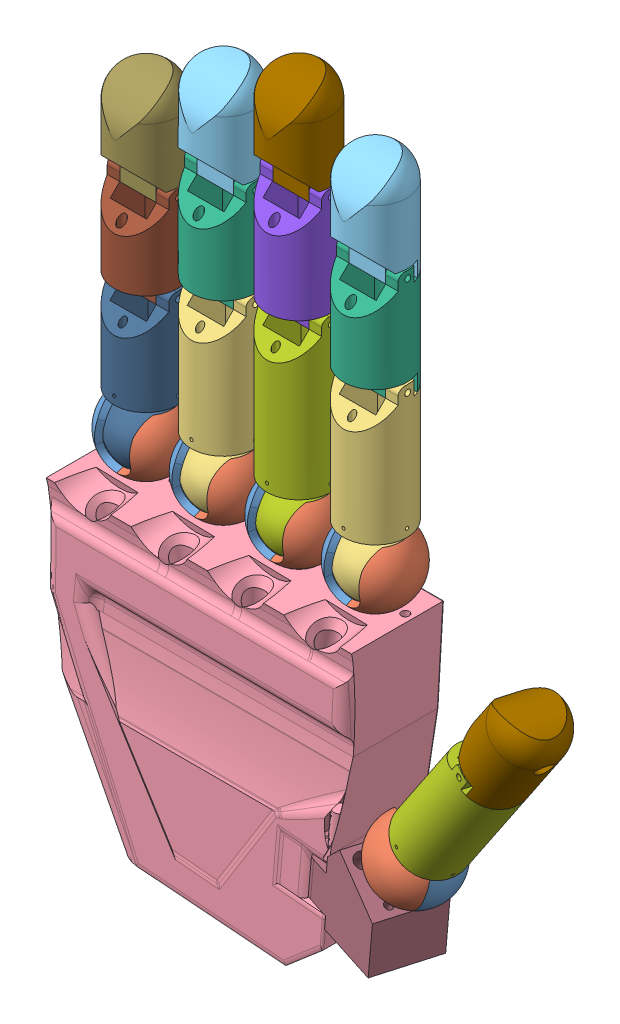
SolidWorks assembly Resized_Assembly, configuration Default. Lengths in mm.
Overall size (156.9 181.99 84.04).
27 component instances, 13 part files, 59 mates.
Components (placement in the parent):
- Resized_Balljoint_socket_L-1: Resized_Balljoint_socket_L [Default] at origin size (9.96 22.72 18.45)
- Resized_Balljoint_socket_R-2: Resized_Balljoint_socket_R [Default] at (-2.2321 0.0027 0.0009) size (9.98 22.72 18.51)
- Resized_BaseDigit_Point&Ring-2: Resized_BaseDigit_Point&Ring [Default] at (-1.1155 37.7951 -0.2751) x (0 -1 0) z (1 0 0) size (50.02 16 16)
- Resized_PalmBody-1: Resized_PalmBody [Default] at (-17.9073 -92.6065 3.3865) x (0.996151 -0.087649 0) z (0 0 1) size (77.61 77.02 24.74)
- Resized_TipDigit_Point&Ring-1: Resized_TipDigit_Point&Ring [Default] at (-1.116 83.4643 -0.063) x (0 -1 0) z (0 0 1) size (25.82 16 16)
- Resized_MiddleDigit2_Point&Ring-2: Resized_MiddleDigit2_Point&Ring [Default] at (-1.116 39.7825 -0.175) x (0 1 0) z (-1 0 0) size (28.43 16 16)
- Resized_BaseDigit_Mid-1: Resized_BaseDigit_Mid [Default] at (-20.5187 37.7951 -0.4783) x (0 -1 0) z (1 0 0) size (55.19 16 16)
- Resized_Balljoint_socket_L-2: Resized_Balljoint_socket_L [Default] at (-19.4032 0 -0.2032) size (9.96 22.72 18.45)
- Resized_Balljoint_socket_R-3: Resized_Balljoint_socket_R [Default] at (-21.6353 0.0027 -0.2023) size (9.98 22.72 18.51)
- Resized_MiddleDigit2_Mid-1: Resized_MiddleDigit2_Mid [Default] at (-20.5192 47.7951 -0.3782) x (0 1 0) z (-1 0 0) size (31.27 16 16)
- Resized_TipDigit_Mid-1: Resized_TipDigit_Mid [Default] at (-20.5192 91.4769 -0.2662) x (0 -1 0) z (0 0 1) size (25.82 16 16)
- Resized_BaseDigit_Point&Ring-3: Resized_BaseDigit_Point&Ring [Default] at (-39.5155 37.7951 -0.4783) x (0 -1 0) z (1 0 0) size (50.02 16 16)
- Resized_MiddleDigit2_Point&Ring-3: Resized_MiddleDigit2_Point&Ring [Default] at (-39.516 39.7825 -0.3782) x (0 1 0) z (-1 0 0) size (28.43 16 16)
- Resized_TipDigit_Point&Ring-2: Resized_TipDigit_Point&Ring [Default] at (-39.516 83.4643 -0.2662) x (0 -1 0) z (0 0 1) size (25.82 16 16)
- Resized_Balljoint_socket_L-3: Resized_Balljoint_socket_L [Default] at (-57.6 0 0) size (9.96 22.72 18.45)
- Resized_Balljoint_socket_R-4: Resized_Balljoint_socket_R [Default] at (-59.8321 0.0027 0.0009) size (9.98 22.72 18.51)
- Resized_Balljoint_socket_L-4: Resized_Balljoint_socket_L [Default] at (-38.4 0 -0.2032) size (9.96 22.72 18.45)
- Resized_Balljoint_socket_R-5: Resized_Balljoint_socket_R [Default] at (-40.6321 0.0027 -0.2023) size (9.98 22.72 18.51)
- Resized_BaseDigit_Pinky-1: Resized_BaseDigit_Pinky [Default] at (-58.7155 37.7951 -0.2751) x (0 -1 0) z (1 0 0) size (41.59 16 16)
- Resized_MiddleDigit2_Pinky-1: Resized_MiddleDigit2_Pinky [Default] at (-58.716 31.3556 -0.175) x (0 1 0) z (-1 0 0) size (25.76 16 16)
- Resized_TipDigit_Pinky-1: Resized_TipDigit_Pinky [Default] at (-58.716 72.3658 -0.063) x (0 -1 0) z (0 0 1) size (25.82 16 16)
- ThumbAssembly-1: ThumbAssembly [Default] at (61.7603 -46.346 28.7176) x (-0.57167 0.476518 -0.667925) z (0.790465 0.538051 -0.292689) size (24.84 62.95 83.3)
  - Resized_TipDigit_Mid-1: Resized_TipDigit_Mid [Default] at (31.6152 29.016 26.2641) x (0.039241 -0.519455 -0.853596) z (0.868647 0.439954 -0.2278) size (25.82 16 16)
  - Resized_BaseDigit_Mid-1: Resized_BaseDigit_Mid [Default] at (32.4513 15.4119 4.11) x (0.039241 -0.519455 -0.853596) z (-0.493875 0.732535 -0.468487) size (55.19 16 16)
  - Resized_Balljoint_socket_L-1: Resized_Balljoint_socket_L [Default] at (34.0231 -3.2273 -28.7523) x (-0.15904 0.840118 -0.518564) z (0.986492 0.156105 -0.049647) size (9.96 22.72 18.45)
  - Resized_Balljoint_socket_R-1: Resized_Balljoint_socket_R [Default] at (34.3788 -5.101 -27.5926) x (-0.15904 0.840118 -0.518564) z (0.986492 0.156105 -0.049647) size (9.98 22.72 18.51)
- Resized_ThumbMount1-1: Resized_ThumbMount1 [Default] at (-23.7476 -83.2413 -8.6435) x (0.964509 -0.084865 0.250041) z (-0.249078 0.021916 0.968235) size (25.43 20.1 16)
Mates (geometry in assembly coordinates):
- Coincident2: coincident anti-aligned: plane of Resized_Balljoint_socket_L-1 through (-1.116 -0.8979 -0.2277) normal (1 0 0); plane of Resized_Balljoint_socket_R-2 through (-1.116 -0.8979 -0.2277) normal (-1 0 0)
- Concentric1: concentric aligned: circle of Resized_Balljoint_socket_L-1; circle of Resized_Balljoint_socket_R-2
- Concentric2: concentric: sphere of Resized_Balljoint_socket_L-1; sphere of Resized_BaseDigit_Point&Ring-2
- Parallel4: parallel aligned: plane of Resized_Balljoint_socket_L-1 through (-4.6144 -8.8979 3.2707) normal (0 0 1); plane of Resized_Balljoint_socket_R-2 through (-4.6144 -8.8979 3.2707) normal (0 0 1)
- Coincident10: coincident anti-aligned: plane of Resized_Balljoint_socket_R-2 through (-1.116 -16.0979 -0.2277) normal (0 -1 0); plane of Resized_PalmBody-1 through (-18.3059 -16.0979 3.8025) normal (0 1 0)
- Coincident11: coincident anti-aligned: plane of Resized_Balljoint_socket_R-2 through (2.3824 -8.8979 -3.7261) normal (1 0 0); plane of Resized_PalmBody-1 through (2.3824 -16.0979 3.8025) normal (-1 0 0)
- Coincident12: coincident anti-aligned: plane of Resized_Balljoint_socket_R-2 through (-4.6144 -8.8979 3.2707) normal (0 0 1); plane of Resized_PalmBody-1 through (-18.3059 -16.0979 3.2707) normal (0 0 -1)
- Concentric11: concentric anti-aligned: cylinder of Resized_BaseDigit_Point&Ring-2 through (-1.116 12.8221 -0.2277) axis (0 1 0) radius 8; cylinder of Resized_MiddleDigit2_Point&Ring-2 through (-1.116 57.2221 -0.2277) axis (0 -1 0) radius 8
- Concentric12: concentric aligned: circle of Resized_BaseDigit_Point&Ring-2; circle of Resized_MiddleDigit2_Point&Ring-2
- Concentric13: concentric aligned: circle of Resized_TipDigit_Point&Ring-1; circle of Resized_MiddleDigit2_Point&Ring-2
- Concentric14: concentric anti-aligned: cylinder of Resized_TipDigit_Point&Ring-1 through (-1.116 65.8541 -0.2277) axis (0 1 0) radius 8; cylinder of Resized_MiddleDigit2_Point&Ring-2 through (-1.116 57.2221 -0.2277) axis (0 -1 0) radius 8
- Parallel8: parallel anti-aligned: plane of Resized_PalmBody-1 through (-18.3059 -8.8979 3.8025) normal (0 1 0); plane of Resized_BaseDigit_Mid-1 through (-20.5192 8.0221 -0.4309) normal (0 -1 0)
- Coincident19: coincident anti-aligned: plane of Resized_Balljoint_socket_L-2 through (-20.5192 -0.8979 -0.4309) normal (1 0 0); plane of Resized_Balljoint_socket_R-3 through (-20.5192 -0.8979 -0.4309) normal (-1 0 0)
- Coincident21: coincident anti-aligned: circle of Resized_Balljoint_socket_L-2; circle of Resized_Balljoint_socket_R-3
- Concentric18: concentric: sphere of Resized_Balljoint_socket_L-2; sphere of Resized_Balljoint_socket_R-3
- Coincident22: coincident anti-aligned: plane of Resized_PalmBody-1 through (-24.0176 -16.0979 3.8025) normal (1 0 0); plane of Resized_Balljoint_socket_L-2 through (-24.0176 -8.8979 -3.9293) normal (-1 0 0)
- Coincident23: coincident anti-aligned: plane of Resized_PalmBody-1 through (-18.3059 -16.0979 -3.9293) normal (0 0 1); plane of Resized_Balljoint_socket_L-2 through (-24.0176 -8.8979 -3.9293) normal (0 0 -1)
- Coincident24: coincident anti-aligned: plane of Resized_PalmBody-1 through (-18.3059 -16.0979 3.8025) normal (0 1 0); plane of Resized_Balljoint_socket_L-2 through (-20.5192 -16.0979 -0.4309) normal (0 -1 0)
- Concentric19: concentric: sphere of Resized_BaseDigit_Mid-1; sphere of Resized_Balljoint_socket_R-3
- Parallel10: parallel anti-aligned: plane of Resized_BaseDigit_Point&Ring-2 through (0.084 -8.7987 -5.6277) normal (0 0 -1); plane of Resized_PalmBody-1 through (-18.3059 -16.0979 -3.9293) normal (0 0 1)
- Parallel11: parallel anti-aligned: plane of Resized_PalmBody-1 through (-18.3059 -16.0979 -3.9293) normal (0 0 1); plane of Resized_BaseDigit_Mid-1 through (-19.3192 -8.7987 -5.8309) normal (0 0 -1)
- Parallel12: parallel anti-aligned: plane of Resized_BaseDigit_Point&Ring-2 through (0.084 -8.7987 -2.4277) normal (1 0 0); plane of Resized_PalmBody-1 through (2.3824 -16.0979 3.8025) normal (-1 0 0)
- Parallel13: parallel anti-aligned: plane of Resized_PalmBody-1 through (-16.8176 -16.0979 3.8025) normal (-1 0 0); plane of Resized_BaseDigit_Mid-1 through (-19.3192 -8.7987 -2.6309) normal (1 0 0)
- Concentric20: concentric aligned: circle of Resized_BaseDigit_Mid-1; circle of Resized_MiddleDigit2_Mid-1
- Concentric21: concentric anti-aligned: cylinder of Resized_BaseDigit_Mid-1 through (-20.5192 12.8221 -0.4309) axis (0 1 0) radius 8; cylinder of Resized_MiddleDigit2_Mid-1 through (-20.5192 65.2347 -0.4309) axis (0 -1 0) radius 8
- Concentric24: concentric anti-aligned: circle of Resized_MiddleDigit2_Mid-1; circle of Resized_TipDigit_Mid-1
- Concentric25: concentric anti-aligned: cylinder of Resized_MiddleDigit2_Mid-1 through (-20.5192 65.2347 -0.4309) axis (0 -1 0) radius 8; cylinder of Resized_TipDigit_Mid-1 through (-20.5192 73.8667 -0.4309) axis (0 1 0) radius 8
- Concentric26: concentric anti-aligned: circle of Resized_Balljoint_socket_L-3; circle of Resized_Balljoint_socket_R-4
- Coincident32: coincident anti-aligned: plane of Resized_Balljoint_socket_L-3 through (-58.716 -0.8979 -0.2277) normal (1 0 0); plane of Resized_Balljoint_socket_R-4 through (-58.716 -0.8979 -0.2277) normal (-1 0 0)
- Concentric27: concentric: sphere of Resized_Balljoint_socket_L-3; sphere of Resized_Balljoint_socket_R-4
- Coincident33: coincident anti-aligned: plane of Resized_PalmBody-1 through (-18.3059 -16.0979 3.2707) normal (0 0 -1); plane of Resized_Balljoint_socket_R-4 through (-62.2144 -8.8979 3.2707) normal (0 0 1)
- Coincident34: coincident anti-aligned: plane of Resized_PalmBody-1 through (-55.2176 -16.0979 3.8025) normal (-1 0 0); plane of Resized_Balljoint_socket_R-4 through (-55.2176 -8.8979 -3.7261) normal (1 0 0)
- Coincident35: coincident anti-aligned: plane of Resized_PalmBody-1 through (-18.3059 -16.0979 3.8025) normal (0 1 0); plane of Resized_Balljoint_socket_R-4 through (-58.716 -16.0979 -0.2277) normal (0 -1 0)
- Coincident36: coincident anti-aligned: circle of Resized_Balljoint_socket_L-4; circle of Resized_Balljoint_socket_R-5
- Concentric28: concentric: sphere of Resized_Balljoint_socket_L-4; sphere of Resized_Balljoint_socket_R-5
- Coincident37: coincident anti-aligned: plane of Resized_PalmBody-1 through (-36.0176 -16.0979 3.8025) normal (-1 0 0); plane of Resized_Balljoint_socket_R-5 through (-36.0176 -8.8979 -3.9293) normal (1 0 0)
- Coincident38: coincident anti-aligned: plane of Resized_PalmBody-1 through (-18.3059 -16.0979 -3.9293) normal (0 0 1); plane of Resized_Balljoint_socket_R-5 through (-43.0144 -8.8979 -3.9293) normal (0 0 -1)
- Coincident39: coincident anti-aligned: plane of Resized_PalmBody-1 through (-18.3059 -16.0979 3.8025) normal (0 1 0); plane of Resized_Balljoint_socket_R-5 through (-39.516 -16.0979 -0.4309) normal (0 -1 0)
- Concentric29: concentric: sphere of Resized_BaseDigit_Point&Ring-3; sphere of Resized_Balljoint_socket_L-4
- Parallel14: parallel aligned: plane of Resized_BaseDigit_Point&Ring-3 through (-38.316 -8.7987 -5.8309) normal (0 0 -1); plane of Resized_Balljoint_socket_R-5 through (-43.0144 -8.8979 -3.9293) normal (0 0 -1)
- Parallel15: parallel aligned: plane of Resized_BaseDigit_Point&Ring-3 through (-38.316 -8.7987 -2.6309) normal (1 0 0); plane of Resized_Balljoint_socket_R-5 through (-36.0176 -8.8979 -3.9293) normal (1 0 0)
- Concentric30: concentric anti-aligned: circle of Resized_BaseDigit_Point&Ring-3; circle of Resized_MiddleDigit2_Point&Ring-3
- Concentric31: concentric anti-aligned: cylinder of Resized_BaseDigit_Point&Ring-3 through (-39.516 12.8221 -0.4309) axis (0 1 0) radius 8; cylinder of Resized_MiddleDigit2_Point&Ring-3 through (-39.516 57.2221 -0.4309) axis (0 -1 0) radius 8
- Concentric32: concentric aligned: circle of Resized_MiddleDigit2_Point&Ring-3; circle of Resized_TipDigit_Point&Ring-2
- Concentric33: concentric anti-aligned: cylinder of Resized_MiddleDigit2_Point&Ring-3 through (-39.516 57.2221 -0.4309) axis (0 -1 0) radius 8; cylinder of Resized_TipDigit_Point&Ring-2 through (-39.516 65.8541 -0.4309) axis (0 1 0) radius 8
- Concentric34: concentric: sphere of Resized_Balljoint_socket_L-3; sphere of Resized_BaseDigit_Pinky-1
- Parallel16: parallel anti-aligned: plane of Resized_PalmBody-1 through (-18.3059 -16.0979 -3.9293) normal (0 0 1); plane of Resized_BaseDigit_Pinky-1 through (-57.516 -8.7987 -5.6277) normal (0 0 -1)
- Parallel17: parallel anti-aligned: plane of Resized_PalmBody-1 through (-55.2176 -16.0979 3.8025) normal (-1 0 0); plane of Resized_BaseDigit_Pinky-1 through (-57.516 -8.7987 -2.4277) normal (1 0 0)
- Concentric35: concentric aligned: circle of Resized_BaseDigit_Pinky-1; circle of Resized_MiddleDigit2_Pinky-1
- Concentric36: concentric anti-aligned: cylinder of Resized_BaseDigit_Pinky-1 through (-58.716 4.3951 -0.2277) axis (0 1 0) radius 8; cylinder of Resized_MiddleDigit2_Pinky-1 through (-58.716 48.7951 -0.2277) axis (0 -1 0) radius 8
- Concentric37: concentric aligned: circle of Resized_MiddleDigit2_Pinky-1; circle of Resized_TipDigit_Pinky-1
- Concentric38: concentric anti-aligned: cylinder of Resized_MiddleDigit2_Pinky-1 through (-58.716 48.7951 -0.2277) axis (0 -1 0) radius 8; cylinder of Resized_TipDigit_Pinky-1 through (-58.716 54.7556 -0.2277) axis (0 1 0) radius 8
- Concentric39: concentric anti-aligned: circle of Resized_PalmBody-1; circle of ?
- Coincident40: coincident anti-aligned: plane of Resized_PalmBody-1 through (2.4599 -67.6937 -8.2055) normal (0.087649 0.996151 0); plane of ? through (4.7139 -67.892 14.8025) normal (-0.087649 -0.996151 0)
- Concentric40: concentric aligned: circle of Resized_PalmBody-1; circle of Resized_ThumbMount1-1
- Coincident42: coincident anti-aligned: plane of Resized_PalmBody-1 through (2.4599 -67.6937 -8.2055) normal (0.087649 0.996151 0); plane of Resized_ThumbMount1-1 through (3.2471 -67.763 16.62) normal (-0.087649 -0.996151 0)
- Coincident43: coincident anti-aligned: plane of ThumbAssembly-1/Resized_Balljoint_socket_L-1 through (19.8053 -58.0961 9.1869) normal (0.503735 -0.229328 -0.832862); plane of Resized_ThumbMount1-1 through (15.7452 -63.9875 8.3534) normal (-0.503735 0.229328 0.832862)
- Coincident44: coincident anti-aligned: plane of ThumbAssembly-1/Resized_Balljoint_socket_L-1 through (15.3446 -54.2345 5.4257) normal (-0.637521 0.551908 -0.537555); plane of Resized_ThumbMount1-1 through (11.1475 -60.0072 4.4766) normal (0.637521 -0.551908 0.537555)
- Coincident45: coincident anti-aligned: plane of ThumbAssembly-1/Resized_Balljoint_socket_L-1 through (11.6155 -61.1357 9.2709) normal (-0.58294 -0.801752 -0.131814); plane of Resized_ThumbMount1-1 through (2.3247 -52.7771 -0.4814) normal (0.58294 0.801752 0.131814)
